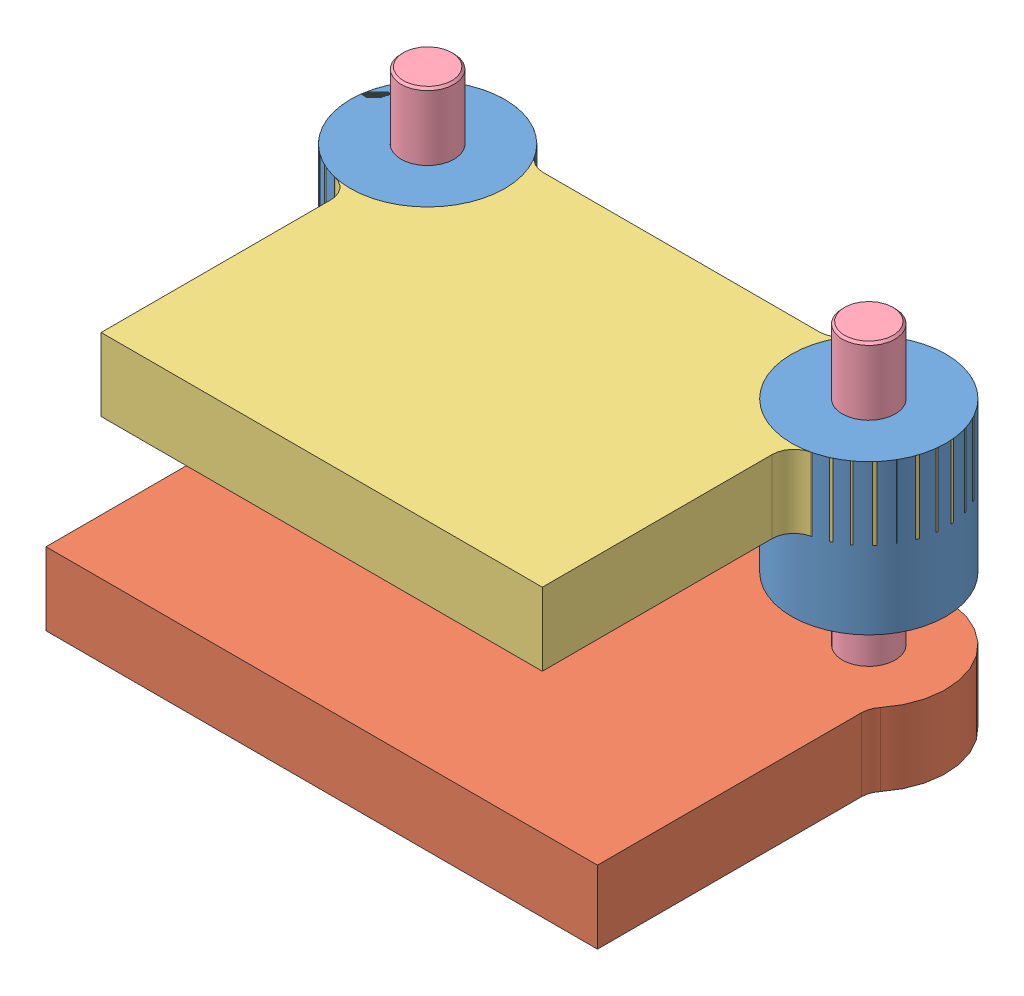
SolidWorks assembly Assem3, configuration Default. Lengths in mm.
Overall size (270 160 183).
6 component instances, 4 part files, 10 mates.
Components (placement in the parent):
- boosh-1: boosh [Default] at (164.7028 -120.7982 130.78) size (70 68 70)
- boosh-2: boosh [Default] at (-35.2972 -120.7982 130.78) size (70 68 70)
- kafsakepaiini-1: kafsakepaiini [Default] at (64.7028 -182.4208 278.78) size (270 33 183)
- kafsake balaii-1: kafsake balaii [Default] at (64.7028 -85.7982 278.78) size (270 33 183)
- mile-1: mile [Default] at (164.7028 -182.4208 130.78) size (24 160 24)
- mile-2: mile [Default] at (-35.2972 -182.4208 130.78) size (24 160 24)
Mates (geometry in assembly coordinates):
- Concentric1: concentric aligned: cylinder of kafsakepaiini-1 through (164.7028 -149.4208 130.78) axis (0 -1 0) radius 12; cylinder of mile-1 through (164.7028 -22.4208 130.78) axis (0 -1 0) radius 12
- Coincident1: coincident anti-aligned: plane of kafsakepaiini-1 through (-35.2972 -182.4208 130.78) normal (0 -1 0); circle of mile-1
- Concentric2: concentric aligned: cylinder of kafsakepaiini-1 through (-35.2972 -149.4208 130.78) axis (0 -1 0) radius 12; cylinder of mile-2 through (-35.2972 -22.4208 130.78) axis (0 -1 0) radius 12
- Coincident2: coincident aligned: plane of kafsakepaiini-1 through (-35.2972 -182.4208 130.78) normal (0 -1 0); plane of mile-2 through (-35.2972 -182.4208 130.78) normal (0 -1 0)
- Concentric3: concentric aligned: cylinder of boosh-1 through (164.7028 -52.7982 130.78) axis (0 -1 0) radius 35; cylinder of kafsake balaii-1 through (164.7028 -52.7982 130.78) axis (0 -1 0) radius 30
- Coincident3: coincident aligned: plane of boosh-1 through (164.7028 -52.7982 130.78) normal (0 1 0); plane of kafsake balaii-1 through (-35.2972 -52.7982 130.78) normal (0 1 0)
- Concentric4: concentric aligned: cylinder of boosh-2 through (-35.2972 -52.7982 130.78) axis (0 -1 0) radius 35; cylinder of kafsake balaii-1 through (-35.2972 -52.7982 130.78) axis (0 -1 0) radius 30
- Coincident4: coincident aligned: plane of boosh-2 through (-35.2972 -52.7982 130.78) normal (0 1 0); plane of kafsake balaii-1 through (-35.2972 -52.7982 130.78) normal (0 1 0)
- Concentric5: concentric aligned: cylinder of boosh-1 through (164.7028 -52.7982 130.78) axis (0 -1 0) radius 12; cylinder of mile-1 through (164.7028 -22.4208 130.78) axis (0 -1 0) radius 12
- Concentric6: concentric aligned: cylinder of boosh-2 through (-35.2972 -52.7982 130.78) axis (0 -1 0) radius 12; cylinder of mile-2 through (-35.2972 -22.4208 130.78) axis (0 -1 0) radius 12
